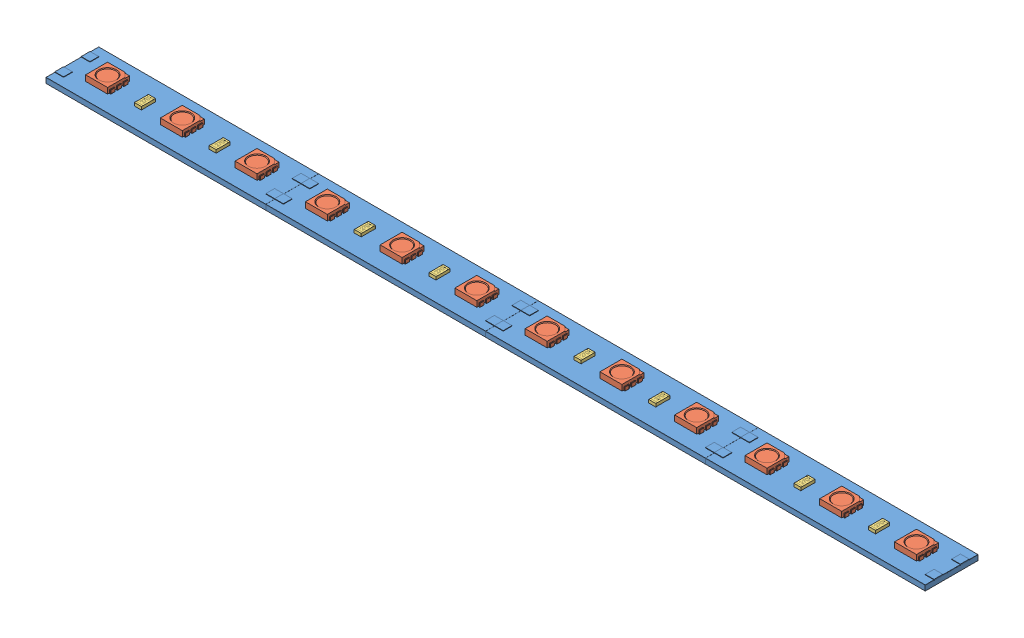
SolidWorks assembly 1mLedStrip.STEP, configuration Default. Lengths in mm.
Overall size (200.09 2.7 12.09).
120 component instances, 3 part files, 0 mates.
Components (placement in the parent):
- stripPad.STEP-1: stripPad.STEP [Default] at (-20.1195 23.8233 53.0068) size (50.09 1.3 12.09)
- led5050.STEP-1: led5050.STEP [Default] at (-14.6195 25.2233 49.5068) size (5.4 1.5 5)
- Resistor1206.STEP-1: Resistor1206.STEP [Default] at (-2.8195 25.0233 48.6068) x (0 0 -1) z (1 0 0) size (3.2 0.7 1.6)
- led5050.STEP-2: led5050.STEP [Default] at (2.3805 25.2233 49.5068) size (5.4 1.5 5)
- led5050.STEP-3: led5050.STEP [Default] at (19.3805 25.2233 49.5068) size (5.4 1.5 5)
- Resistor1206.STEP-2: Resistor1206.STEP [Default] at (14.1805 25.0233 48.6068) x (0 0 -1) z (1 0 0) size (3.2 0.7 1.6)
- led5050.STEP-4: led5050.STEP [Default] at (35.3805 25.2233 49.5068) size (5.4 1.5 5)
- led5050.STEP-5: led5050.STEP [Default] at (85.3805 25.2233 49.5068) size (5.4 1.5 5)
- led5050.STEP-6: led5050.STEP [Default] at (135.3805 25.2233 49.5068) size (5.4 1.5 5)
- led5050.STEP-7: led5050.STEP [Default] at (185.3805 25.2233 49.5068) size (5.4 1.5 5) (suppressed, hidden)
- led5050.STEP-8: led5050.STEP [Default] at (235.3805 25.2233 49.5068) size (5.4 1.5 5) (suppressed, hidden)
- led5050.STEP-9: led5050.STEP [Default] at (285.3805 25.2233 49.5068) size (5.4 1.5 5) (suppressed, hidden)
- led5050.STEP-10: led5050.STEP [Default] at (335.3805 25.2233 49.5068) size (5.4 1.5 5) (suppressed, hidden)
- led5050.STEP-11: led5050.STEP [Default] at (385.3805 25.2233 49.5068) size (5.4 1.5 5) (suppressed, hidden)
- led5050.STEP-12: led5050.STEP [Default] at (435.3805 25.2233 49.5068) size (5.4 1.5 5) (suppressed, hidden)
- led5050.STEP-13: led5050.STEP [Default] at (485.3805 25.2233 49.5068) size (5.4 1.5 5) (suppressed, hidden)
- led5050.STEP-14: led5050.STEP [Default] at (535.3805 25.2233 49.5068) size (5.4 1.5 5) (suppressed, hidden)
- led5050.STEP-15: led5050.STEP [Default] at (585.3805 25.2233 49.5068) size (5.4 1.5 5) (suppressed, hidden)
- led5050.STEP-16: led5050.STEP [Default] at (635.3805 25.2233 49.5068) size (5.4 1.5 5) (suppressed, hidden)
- led5050.STEP-17: led5050.STEP [Default] at (685.3805 25.2233 49.5068) size (5.4 1.5 5) (suppressed, hidden)
- led5050.STEP-18: led5050.STEP [Default] at (735.3805 25.2233 49.5068) size (5.4 1.5 5) (suppressed, hidden)
- led5050.STEP-19: led5050.STEP [Default] at (785.3805 25.2233 49.5068) size (5.4 1.5 5) (suppressed, hidden)
- led5050.STEP-20: led5050.STEP [Default] at (835.3805 25.2233 49.5068) size (5.4 1.5 5) (suppressed, hidden)
- led5050.STEP-21: led5050.STEP [Default] at (885.3805 25.2233 49.5068) size (5.4 1.5 5) (suppressed, hidden)
- led5050.STEP-22: led5050.STEP [Default] at (935.3805 25.2233 49.5068) size (5.4 1.5 5) (suppressed, hidden)
- led5050.STEP-23: led5050.STEP [Default] at (52.3805 25.2233 49.5068) size (5.4 1.5 5)
- led5050.STEP-24: led5050.STEP [Default] at (102.3805 25.2233 49.5068) size (5.4 1.5 5)
- led5050.STEP-25: led5050.STEP [Default] at (152.3805 25.2233 49.5068) size (5.4 1.5 5)
- led5050.STEP-26: led5050.STEP [Default] at (202.3805 25.2233 49.5068) size (5.4 1.5 5) (suppressed, hidden)
- led5050.STEP-27: led5050.STEP [Default] at (252.3805 25.2233 49.5068) size (5.4 1.5 5) (suppressed, hidden)
- led5050.STEP-28: led5050.STEP [Default] at (302.3805 25.2233 49.5068) size (5.4 1.5 5) (suppressed, hidden)
- led5050.STEP-29: led5050.STEP [Default] at (352.3805 25.2233 49.5068) size (5.4 1.5 5) (suppressed, hidden)
- led5050.STEP-30: led5050.STEP [Default] at (402.3805 25.2233 49.5068) size (5.4 1.5 5) (suppressed, hidden)
- led5050.STEP-31: led5050.STEP [Default] at (452.3805 25.2233 49.5068) size (5.4 1.5 5) (suppressed, hidden)
- led5050.STEP-32: led5050.STEP [Default] at (502.3805 25.2233 49.5068) size (5.4 1.5 5) (suppressed, hidden)
- led5050.STEP-33: led5050.STEP [Default] at (552.3805 25.2233 49.5068) size (5.4 1.5 5) (suppressed, hidden)
- led5050.STEP-34: led5050.STEP [Default] at (602.3805 25.2233 49.5068) size (5.4 1.5 5) (suppressed, hidden)
- led5050.STEP-35: led5050.STEP [Default] at (652.3805 25.2233 49.5068) size (5.4 1.5 5) (suppressed, hidden)
- led5050.STEP-36: led5050.STEP [Default] at (702.3805 25.2233 49.5068) size (5.4 1.5 5) (suppressed, hidden)
- led5050.STEP-37: led5050.STEP [Default] at (752.3805 25.2233 49.5068) size (5.4 1.5 5) (suppressed, hidden)
- led5050.STEP-38: led5050.STEP [Default] at (802.3805 25.2233 49.5068) size (5.4 1.5 5) (suppressed, hidden)
- led5050.STEP-39: led5050.STEP [Default] at (852.3805 25.2233 49.5068) size (5.4 1.5 5) (suppressed, hidden)
- led5050.STEP-40: led5050.STEP [Default] at (902.3805 25.2233 49.5068) size (5.4 1.5 5) (suppressed, hidden)
- led5050.STEP-41: led5050.STEP [Default] at (952.3805 25.2233 49.5068) size (5.4 1.5 5) (suppressed, hidden)
- led5050.STEP-42: led5050.STEP [Default] at (69.3805 25.2233 49.5068) size (5.4 1.5 5)
- led5050.STEP-43: led5050.STEP [Default] at (119.3805 25.2233 49.5068) size (5.4 1.5 5)
- led5050.STEP-44: led5050.STEP [Default] at (169.3805 25.2233 49.5068) size (5.4 1.5 5)
- led5050.STEP-45: led5050.STEP [Default] at (219.3805 25.2233 49.5068) size (5.4 1.5 5) (suppressed, hidden)
- led5050.STEP-46: led5050.STEP [Default] at (269.3805 25.2233 49.5068) size (5.4 1.5 5) (suppressed, hidden)
- led5050.STEP-47: led5050.STEP [Default] at (319.3805 25.2233 49.5068) size (5.4 1.5 5) (suppressed, hidden)
- led5050.STEP-48: led5050.STEP [Default] at (369.3805 25.2233 49.5068) size (5.4 1.5 5) (suppressed, hidden)
- led5050.STEP-49: led5050.STEP [Default] at (419.3805 25.2233 49.5068) size (5.4 1.5 5) (suppressed, hidden)
- led5050.STEP-50: led5050.STEP [Default] at (469.3805 25.2233 49.5068) size (5.4 1.5 5) (suppressed, hidden)
- led5050.STEP-51: led5050.STEP [Default] at (519.3805 25.2233 49.5068) size (5.4 1.5 5) (suppressed, hidden)
- led5050.STEP-52: led5050.STEP [Default] at (569.3805 25.2233 49.5068) size (5.4 1.5 5) (suppressed, hidden)
- led5050.STEP-53: led5050.STEP [Default] at (619.3805 25.2233 49.5068) size (5.4 1.5 5) (suppressed, hidden)
- led5050.STEP-54: led5050.STEP [Default] at (669.3805 25.2233 49.5068) size (5.4 1.5 5) (suppressed, hidden)
- led5050.STEP-55: led5050.STEP [Default] at (719.3805 25.2233 49.5068) size (5.4 1.5 5) (suppressed, hidden)
- led5050.STEP-56: led5050.STEP [Default] at (769.3805 25.2233 49.5068) size (5.4 1.5 5) (suppressed, hidden)
- led5050.STEP-57: led5050.STEP [Default] at (819.3805 25.2233 49.5068) size (5.4 1.5 5) (suppressed, hidden)
- led5050.STEP-58: led5050.STEP [Default] at (869.3805 25.2233 49.5068) size (5.4 1.5 5) (suppressed, hidden)
- led5050.STEP-59: led5050.STEP [Default] at (919.3805 25.2233 49.5068) size (5.4 1.5 5) (suppressed, hidden)
- led5050.STEP-60: led5050.STEP [Default] at (969.3805 25.2233 49.5068) size (5.4 1.5 5) (suppressed, hidden)
- stripPad.STEP-2: stripPad.STEP [Default] at (29.8805 23.8233 53.0068) size (50.09 1.3 12.09)
- stripPad.STEP-3: stripPad.STEP [Default] at (79.8805 23.8233 53.0068) size (50.09 1.3 12.09)
- stripPad.STEP-4: stripPad.STEP [Default] at (129.8805 23.8233 53.0068) size (50.09 1.3 12.09)
- stripPad.STEP-5: stripPad.STEP [Default] at (179.8805 23.8233 53.0068) size (50.09 1.3 12.09) (suppressed, hidden)
- stripPad.STEP-6: stripPad.STEP [Default] at (229.8805 23.8233 53.0068) size (50.09 1.3 12.09) (suppressed, hidden)
- stripPad.STEP-7: stripPad.STEP [Default] at (279.8805 23.8233 53.0068) size (50.09 1.3 12.09) (suppressed, hidden)
- stripPad.STEP-8: stripPad.STEP [Default] at (329.8805 23.8233 53.0068) size (50.09 1.3 12.09) (suppressed, hidden)
- stripPad.STEP-9: stripPad.STEP [Default] at (379.8805 23.8233 53.0068) size (50.09 1.3 12.09) (suppressed, hidden)
- stripPad.STEP-10: stripPad.STEP [Default] at (429.8805 23.8233 53.0068) size (50.09 1.3 12.09) (suppressed, hidden)
- stripPad.STEP-11: stripPad.STEP [Default] at (479.8805 23.8233 53.0068) size (50.09 1.3 12.09) (suppressed, hidden)
- stripPad.STEP-12: stripPad.STEP [Default] at (529.8805 23.8233 53.0068) size (50.09 1.3 12.09) (suppressed, hidden)
- stripPad.STEP-13: stripPad.STEP [Default] at (579.8805 23.8233 53.0068) size (50.09 1.3 12.09) (suppressed, hidden)
- stripPad.STEP-14: stripPad.STEP [Default] at (629.8805 23.8233 53.0068) size (50.09 1.3 12.09) (suppressed, hidden)
- stripPad.STEP-15: stripPad.STEP [Default] at (679.8805 23.8233 53.0068) size (50.09 1.3 12.09) (suppressed, hidden)
- stripPad.STEP-16: stripPad.STEP [Default] at (729.8805 23.8233 53.0068) size (50.09 1.3 12.09) (suppressed, hidden)
- stripPad.STEP-17: stripPad.STEP [Default] at (779.8805 23.8233 53.0068) size (50.09 1.3 12.09) (suppressed, hidden)
- stripPad.STEP-18: stripPad.STEP [Default] at (829.8805 23.8233 53.0068) size (50.09 1.3 12.09) (suppressed, hidden)
- stripPad.STEP-19: stripPad.STEP [Default] at (879.8805 23.8233 53.0068) size (50.09 1.3 12.09) (suppressed, hidden)
- stripPad.STEP-20: stripPad.STEP [Default] at (929.8805 23.8233 53.0068) size (50.09 1.3 12.09) (suppressed, hidden)
- Resistor1206.STEP-3: Resistor1206.STEP [Default] at (47.1805 25.0233 48.6068) x (0 0 -1) z (1 0 0) size (3.2 0.7 1.6)
- Resistor1206.STEP-4: Resistor1206.STEP [Default] at (97.1805 25.0233 48.6068) x (0 0 -1) z (1 0 0) size (3.2 0.7 1.6)
- Resistor1206.STEP-5: Resistor1206.STEP [Default] at (147.1805 25.0233 48.6068) x (0 0 -1) z (1 0 0) size (3.2 0.7 1.6)
- Resistor1206.STEP-6: Resistor1206.STEP [Default] at (197.1805 25.0233 48.6068) x (0 0 -1) z (1 0 0) size (3.2 0.7 1.6) (suppressed, hidden)
- Resistor1206.STEP-7: Resistor1206.STEP [Default] at (247.1805 25.0233 48.6068) x (0 0 -1) z (1 0 0) size (3.2 0.7 1.6) (suppressed, hidden)
- Resistor1206.STEP-8: Resistor1206.STEP [Default] at (297.1805 25.0233 48.6068) x (0 0 -1) z (1 0 0) size (3.2 0.7 1.6) (suppressed, hidden)
- Resistor1206.STEP-9: Resistor1206.STEP [Default] at (347.1805 25.0233 48.6068) x (0 0 -1) z (1 0 0) size (3.2 0.7 1.6) (suppressed, hidden)
- Resistor1206.STEP-10: Resistor1206.STEP [Default] at (397.1805 25.0233 48.6068) x (0 0 -1) z (1 0 0) size (3.2 0.7 1.6) (suppressed, hidden)
- Resistor1206.STEP-11: Resistor1206.STEP [Default] at (447.1805 25.0233 48.6068) x (0 0 -1) z (1 0 0) size (3.2 0.7 1.6) (suppressed, hidden)
- Resistor1206.STEP-12: Resistor1206.STEP [Default] at (497.1805 25.0233 48.6068) x (0 0 -1) z (1 0 0) size (3.2 0.7 1.6) (suppressed, hidden)
- Resistor1206.STEP-13: Resistor1206.STEP [Default] at (547.1805 25.0233 48.6068) x (0 0 -1) z (1 0 0) size (3.2 0.7 1.6) (suppressed, hidden)
- Resistor1206.STEP-14: Resistor1206.STEP [Default] at (597.1805 25.0233 48.6068) x (0 0 -1) z (1 0 0) size (3.2 0.7 1.6) (suppressed, hidden)
- Resistor1206.STEP-15: Resistor1206.STEP [Default] at (647.1805 25.0233 48.6068) x (0 0 -1) z (1 0 0) size (3.2 0.7 1.6) (suppressed, hidden)
- Resistor1206.STEP-16: Resistor1206.STEP [Default] at (697.1805 25.0233 48.6068) x (0 0 -1) z (1 0 0) size (3.2 0.7 1.6) (suppressed, hidden)
- Resistor1206.STEP-17: Resistor1206.STEP [Default] at (747.1805 25.0233 48.6068) x (0 0 -1) z (1 0 0) size (3.2 0.7 1.6) (suppressed, hidden)
- Resistor1206.STEP-18: Resistor1206.STEP [Default] at (797.1805 25.0233 48.6068) x (0 0 -1) z (1 0 0) size (3.2 0.7 1.6) (suppressed, hidden)
- Resistor1206.STEP-19: Resistor1206.STEP [Default] at (847.1805 25.0233 48.6068) x (0 0 -1) z (1 0 0) size (3.2 0.7 1.6) (suppressed, hidden)
- Resistor1206.STEP-20: Resistor1206.STEP [Default] at (897.1805 25.0233 48.6068) x (0 0 -1) z (1 0 0) size (3.2 0.7 1.6) (suppressed, hidden)
- Resistor1206.STEP-21: Resistor1206.STEP [Default] at (947.1805 25.0233 48.6068) x (0 0 -1) z (1 0 0) size (3.2 0.7 1.6) (suppressed, hidden)
- Resistor1206.STEP-22: Resistor1206.STEP [Default] at (64.1805 25.0233 48.6068) x (0 0 -1) z (1 0 0) size (3.2 0.7 1.6)
- Resistor1206.STEP-23: Resistor1206.STEP [Default] at (114.1805 25.0233 48.6068) x (0 0 -1) z (1 0 0) size (3.2 0.7 1.6)
- Resistor1206.STEP-24: Resistor1206.STEP [Default] at (164.1805 25.0233 48.6068) x (0 0 -1) z (1 0 0) size (3.2 0.7 1.6)
- Resistor1206.STEP-25: Resistor1206.STEP [Default] at (214.1805 25.0233 48.6068) x (0 0 -1) z (1 0 0) size (3.2 0.7 1.6) (suppressed, hidden)
- Resistor1206.STEP-26: Resistor1206.STEP [Default] at (264.1805 25.0233 48.6068) x (0 0 -1) z (1 0 0) size (3.2 0.7 1.6) (suppressed, hidden)
- Resistor1206.STEP-27: Resistor1206.STEP [Default] at (314.1805 25.0233 48.6068) x (0 0 -1) z (1 0 0) size (3.2 0.7 1.6) (suppressed, hidden)
- Resistor1206.STEP-28: Resistor1206.STEP [Default] at (364.1805 25.0233 48.6068) x (0 0 -1) z (1 0 0) size (3.2 0.7 1.6) (suppressed, hidden)
- Resistor1206.STEP-29: Resistor1206.STEP [Default] at (414.1805 25.0233 48.6068) x (0 0 -1) z (1 0 0) size (3.2 0.7 1.6) (suppressed, hidden)
- Resistor1206.STEP-30: Resistor1206.STEP [Default] at (464.1805 25.0233 48.6068) x (0 0 -1) z (1 0 0) size (3.2 0.7 1.6) (suppressed, hidden)
- Resistor1206.STEP-31: Resistor1206.STEP [Default] at (514.1805 25.0233 48.6068) x (0 0 -1) z (1 0 0) size (3.2 0.7 1.6) (suppressed, hidden)
- Resistor1206.STEP-32: Resistor1206.STEP [Default] at (564.1805 25.0233 48.6068) x (0 0 -1) z (1 0 0) size (3.2 0.7 1.6) (suppressed, hidden)
- Resistor1206.STEP-33: Resistor1206.STEP [Default] at (614.1805 25.0233 48.6068) x (0 0 -1) z (1 0 0) size (3.2 0.7 1.6) (suppressed, hidden)
- Resistor1206.STEP-34: Resistor1206.STEP [Default] at (664.1805 25.0233 48.6068) x (0 0 -1) z (1 0 0) size (3.2 0.7 1.6) (suppressed, hidden)
- Resistor1206.STEP-35: Resistor1206.STEP [Default] at (714.1805 25.0233 48.6068) x (0 0 -1) z (1 0 0) size (3.2 0.7 1.6) (suppressed, hidden)
- Resistor1206.STEP-36: Resistor1206.STEP [Default] at (764.1805 25.0233 48.6068) x (0 0 -1) z (1 0 0) size (3.2 0.7 1.6) (suppressed, hidden)
- Resistor1206.STEP-37: Resistor1206.STEP [Default] at (814.1805 25.0233 48.6068) x (0 0 -1) z (1 0 0) size (3.2 0.7 1.6) (suppressed, hidden)
- Resistor1206.STEP-38: Resistor1206.STEP [Default] at (864.1805 25.0233 48.6068) x (0 0 -1) z (1 0 0) size (3.2 0.7 1.6) (suppressed, hidden)
- Resistor1206.STEP-39: Resistor1206.STEP [Default] at (914.1805 25.0233 48.6068) x (0 0 -1) z (1 0 0) size (3.2 0.7 1.6) (suppressed, hidden)
- Resistor1206.STEP-40: Resistor1206.STEP [Default] at (964.1805 25.0233 48.6068) x (0 0 -1) z (1 0 0) size (3.2 0.7 1.6) (suppressed, hidden)
